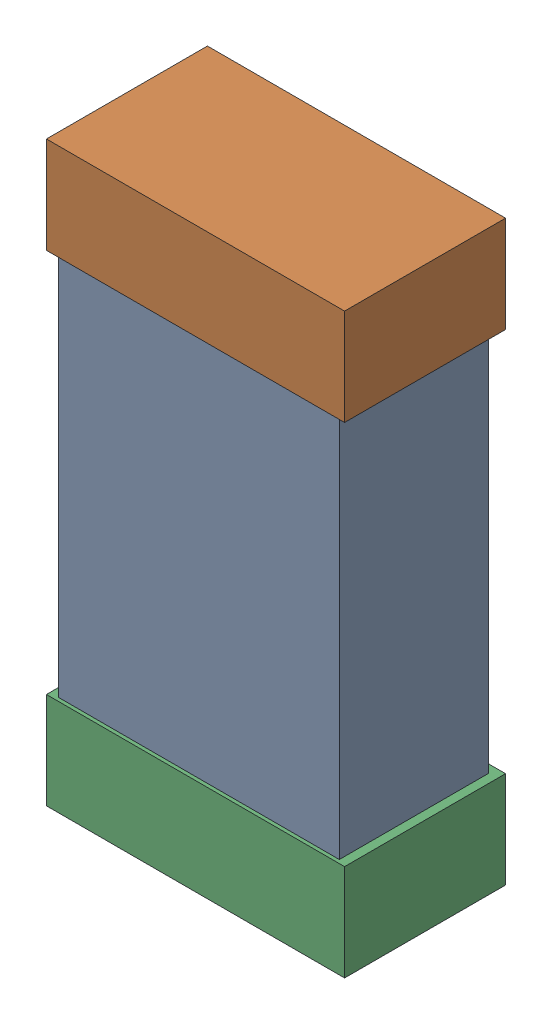
SolidWorks assembly R7, configuration Default. Lengths in mm.
Overall size (0.85 1.65 0.46).
6 component instances, 2 part files, 0 mates.
Components (placement in the parent):
- 432124816_46-1: 432124816_46 [Default] at (29.4959 22.0597 0.025) size (0.8 1.5 0.42)
  - Extruded (1)-1: Extruded (1) [Default] at origin size (0.8 1.5 0.42)
- 432138512_92-1: 432138512_92 [Default] at (29.4959 22.7455 0.001) size (0.85 0.28 0.46)
  - Extruded-1: Extruded [Default] at origin size (0.85 0.28 0.46)
- 432138512_93-1: 432138512_93 [Default] at (29.4959 21.3739 0.001) size (0.85 0.28 0.46)
  - Extruded-1: Extruded [Default] at origin size (0.85 0.28 0.46)
